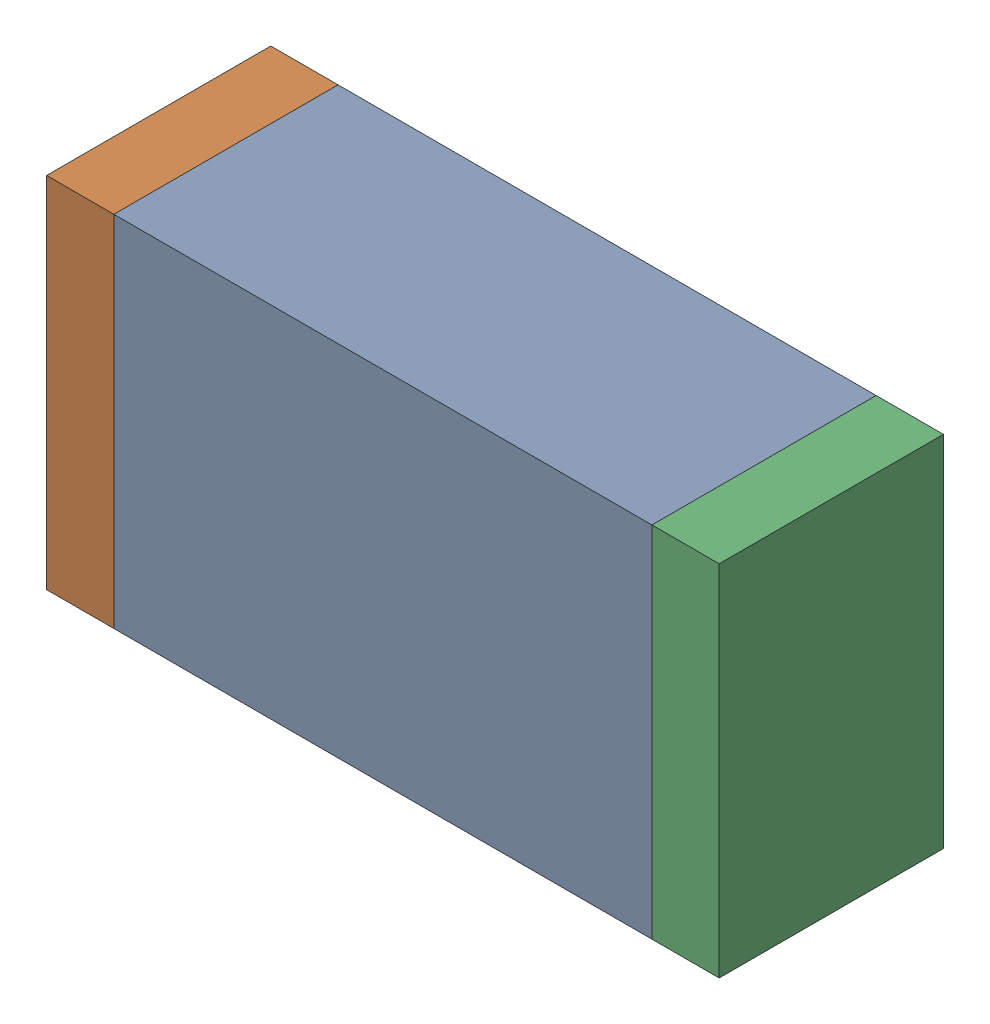
SolidWorks assembly D17, configuration Default. Lengths in mm.
Overall size (1.5 0.8 0.5).
6 component instances, 2 part files, 0 mates.
Components (placement in the parent):
- 836752368-1: 836752368 [Default] at (111.2 32.5 0) size (1.2 0.8 0.5)
  - Extruded-1: Extruded [Default] at origin size (1.2 0.8 0.5)
- 836752496-1: 836752496 [Default] at (110.525 32.5 0) size (0.15 0.8 0.5)
  - Extruded_2-1: Extruded_2 [Default] at origin size (0.15 0.8 0.5)
- 836752496-2: 836752496 [Default] at (111.875 32.5 0) size (0.15 0.8 0.5)
  - Extruded_2-1: Extruded_2 [Default] at origin size (0.15 0.8 0.5)
